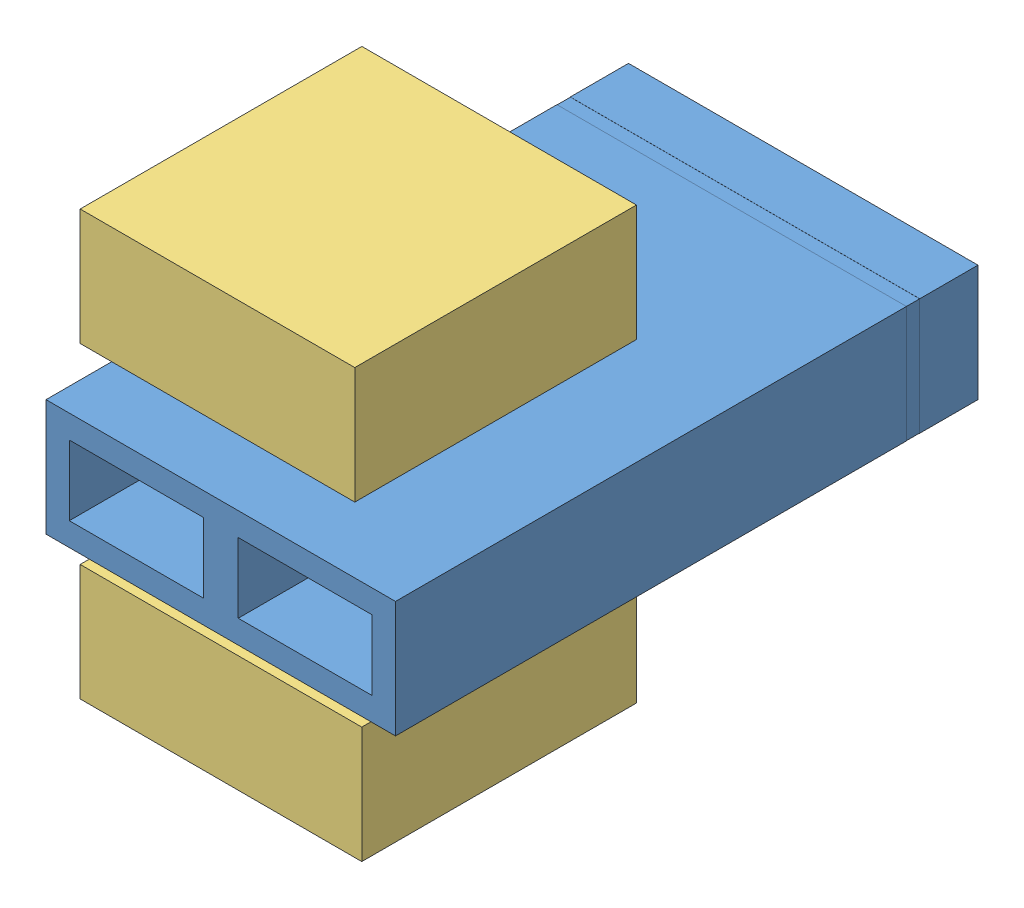
SolidWorks assembly pegsensor1021, configuration Default. Lengths in mm.
Overall size (30 36.42 50).
5 component instances, 3 part files, 18 mates.
Components (placement in the parent):
- 插头-1: 插头 [默认] at (20.1448 26.8849 14.5726) size (30 12.41 50)
- sensor-1: sensor [Default] at (28.9136 8.6727 49.2183) x (1 0 0) z (0 1 0) size (20.42 20.42 3.21)
- sensorbase-1: sensorbase [Default] at (30.1653 35.0971 50.104) x (1 0 0.000158) z (0 1 0) size (23.58 24.17 10)
- sensorbase-2: sensorbase [Default] at (17.6957 8.6727 63.0843) x (-0.000158 0 1) z (0 1 0) size (23.58 24.17 10)
- sensor-2: sensor [Default] at (17.1526 45.0971 37.4573) x (0 0 -1) z (0 -1 0) size (20.42 20.42 3.21)
Mates (geometry in assembly coordinates):
- 相切5: tangent anti-aligned: plane of 插头-1 through (20.1448 21.8849 64.5726) normal (0 -1 0); sphere of sensor-1
- 相切6: tangent anti-aligned: plane of 插头-1 through (20.1448 21.8849 64.5726) normal (0 -1 0); sphere of sensor-1
- 相切7: tangent anti-aligned: plane of 插头-1 through (20.1448 21.8849 64.5726) normal (0 -1 0); sphere of sensor-1
- 重合3: coincident anti-aligned: plane of sensor-1 through (4.401 18.6727 11.2634) normal (0 -1 0); plane of sensorbase-2 through (17.6961 18.6727 61.0416) normal (0 1 0)
- 相切9: tangent anti-aligned: plane of 插头-1 through (20.1448 31.8849 64.5726) normal (0 1 0); sphere of sensor-2
- 相切10: tangent anti-aligned: plane of 插头-1 through (20.1448 31.8849 64.5726) normal (0 1 0); sphere of sensor-2
- 相切11: tangent anti-aligned: plane of 插头-1 through (20.1448 31.8849 64.5726) normal (0 1 0); sphere of sensor-2
- 相切12: tangent anti-aligned: plane of 插头-1 through (20.1448 31.8849 64.5726) normal (0 1 0); sphere of sensor-2
- 相切13: tangent: line of 插头-1 through (5.1448 21.8849 55.9332) axis (1 0 0); sphere of sensor-1
- 相切14: tangent: line of 插头-1 through (5.1448 21.8849 55.9332) axis (1 0 0); sphere of sensor-1
- 相切15: tangent: line of 插头-1 through (5.1448 31.8849 55.9332) axis (1 0 0); sphere of sensor-2
- 相切16: tangent: line of 插头-1 through (5.1448 31.8849 55.9332) axis (1 0 0); sphere of sensor-2
- 重合4: coincident anti-aligned: plane of sensorbase-1 through (30.1653 35.0971 50.104) normal (0 -1 0); plane of sensor-2 through (55.1074 35.0971 61.9699) normal (0 1 0)
- 相切17: tangent anti-aligned: sphere of sensor-2; line of 插头-1 through (10.4376 31.8849 42.8818) axis (0 0 1)
- 相切18: tangent: line of 插头-1 through (10.4376 31.8849 42.8818) axis (0 0 1); sphere of sensor-2
- 相切19: tangent: line of 插头-1 through (10.4376 21.8849 64.5726) axis (0 0 -1); sphere of sensor-1
- 重合5: coincident aligned: plane of sensorbase-1 through (5.6546 45.0971 37.9707) normal (-1 0 -0.000158); plane of sensorbase-2 through (5.6508 93.4072 62.1452) normal (-1 0 -0.000158)
- 重合6: coincident aligned: plane of sensorbase-1 through (29.2262 119.8316 62.1489) normal (-0.000158 0 1); plane of sensorbase-2 through (29.8253 93.4072 62.149) normal (-0.000158 0 1)
